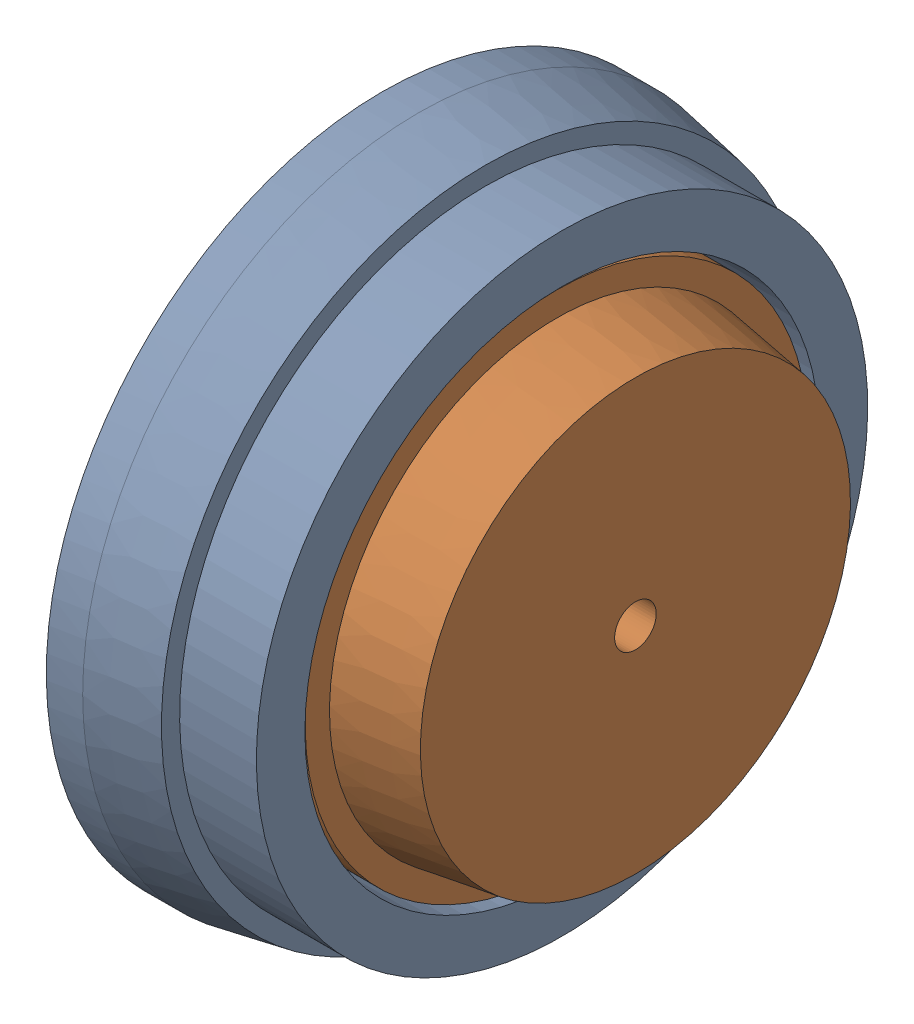
SolidWorks assembly Drive, configuration Default. Lengths in mm.
Overall size (52.77 110.86 110.86).
2 component instances, 2 part files, 0 mates.
Components (placement in the parent):
- Motor_Rotor-1: Motor_Rotor [Default] at (0 157.5 -157.5) x (1 0 0) z (0 -1 0) size (40.67 110.86 110.86)
- Motor_Stator-1: Motor_Stator [Default] at (0 157.5 -157.5) x (1 0 0) z (0 -1 0) size (29.77 82.97 82.97)
